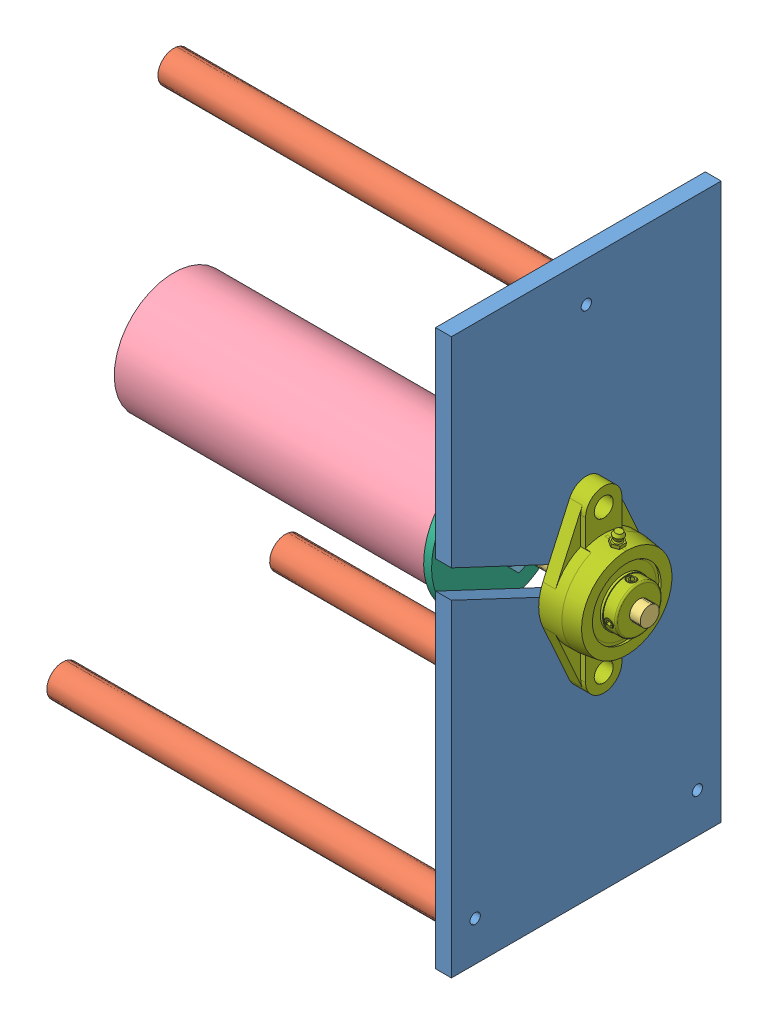
SolidWorks assembly TopRumpf, configuration Standard. Lengths in mm.
Overall size (300 350 170).
11 component instances, 7 part files, 21 mates.
Components (placement in the parent):
- Kopfteil_Rumpf-2: Kopfteil_Rumpf [Standard] at (250 0 0) x (0 0 -1) z (1 0 0) size (170 350 10)
- Kunststoffstab-1: Kunststoffstab [Standard] at (0 150 0) x (0 -0.985047 0.172283) z (1 0 0) size (20 20 250)
- Kunststoffstab-2: Kunststoffstab [Standard] at (0 -150 70) x (0 -0.332904 0.942961) z (1 0 0) size (20 20 250)
- Kunststoffstab-3: Kunststoffstab [Standard] at (0.4347 -150 -70) x (0 -0.626409 -0.779495) z (1 0 0) size (20 20 250)
- Rolle^TopRumpf-1: Rolle^TopRumpf [Standard] at (0 -201.8271 15.2917) x (1 0 0) z (0 0.91625 0.400607) size (300 85 85) (virtual)
  - Rundstahl 8mm-1: Rundstahl 8mm [Standard] at (300 94.8643 178.7981) x (0 0.566472 0.824081) z (-1 0 0) size (12 12 300)
  - Rolle-1: Rolle [Standard] at (0 94.8643 178.7981) x (0 0 -1) z (1 0 0) size (75 75 200)
  - shf12-1: shf12 [Standard] at (205 94.8643 178.7981) size (13.01 28 47)
  - Rollenaufnahme-1: Rollenaufnahme [Standard] at (200 94.8643 178.7981) x (0 0 1) z (-1 0 0) size (85 85 15)
- Baugr2^TopRumpf-1: Baugr2^TopRumpf [Standard] at (185.0438 -39.7683 25.0936) (suppressed, hidden, virtual)
- 24215-12201-1: 24215-12201 [Standard] at (260 0 0) x (0 1 0) z (0 0 -1) size (113 33.3 60)
Mates (geometry in assembly coordinates):
- Deckungsgleich17: coincident: point of Kunststoffstab-2; plane of assembly
- Konzentrisch24: concentric aligned: circle of Kunststoffstab-3; cylinder of Kopfteil_Rumpf-2 through (260 -150 -70) axis (1 0 0) radius 3.25
- Konzentrisch25: concentric aligned: circle of Kunststoffstab-1; circle of Kopfteil_Rumpf-2
- Konzentrisch26: concentric aligned: circle of Kunststoffstab-2; cylinder of Kopfteil_Rumpf-2 through (260 -150 70) axis (1 0 0) radius 3.25
- Deckungsgleich27: coincident anti-aligned: plane of Kunststoffstab-1 through (0 150 0) normal (-1 0 0)
- Parallel7: parallel aligned: plane of Kopfteil_Rumpf-2 through (260 175 -85) normal (0 1 0)
- Deckungsgleich33: coincident anti-aligned: plane of Kopfteil_Rumpf-2 through (250 0 0) normal (-1 0 0); plane of Kunststoffstab-1 through (250 150 0) normal (1 0 0)
- Abstand1: distance = 500 mm aligned: plane of Kunststoffstab-1 through (0 150 0) normal (-1 0 0); plane of Baugr2^TopRumpf-1/Innenring-1 through (500 0 0) normal (-1 0 0)
- Parallel8: parallel aligned: plane of Baugr2^TopRumpf-1 through (185.0438 -39.7683 25.0936) normal (0 0 1)
- Deckungsgleich36: coincident anti-aligned: plane of Baugr1^TopRumpf-1/Rundstahl 8mm-1 through (0 0 0) normal (-1 0 0)
- Deckungsgleich37: coincident: plane of Baugr1^TopRumpf-1/Rundstahl 8mm-1 through (0 0 0) normal (-1 0 0)
- Deckungsgleich38: coincident: unknown of Baugr1^TopRumpf-1/Rundstahl 8mm-1
- Konzentrisch34: concentric aligned: cylinder of Rolle^TopRumpf-1/Rundstahl 8mm-1 through (0 0 0) axis (-1 0 0) radius 6; line of Baugr2^TopRumpf-1/Halbkugel-1 through (540 0 0) axis (-1 0 0)
- Konzentrisch35: concentric aligned: cylinder of Kopfteil_Rumpf-2 through (260 45 0) axis (1 0 0) radius 3.25; cylinder of Baugr1^TopRumpf-1/HousingMitKugellager-1/HousingKugellagerDeckel-2 through (331 25 0) axis (1 0 0) radius 2.75
- Konzentrisch36: concentric aligned: cylinder of Kopfteil_Rumpf-2 through (260 45 0) axis (1 0 0) radius 3.25; cylinder of Baugr1^TopRumpf-1/HousingMitKugellager-1/HousingKugellagerDeckel-2 through (331 25 0) axis (1 0 0) radius 2.75
- Konzentrisch37: concentric aligned: cylinder of Kopfteil_Rumpf-2 through (260 -45 0) axis (1 0 0) radius 3.25; cylinder of Baugr1^TopRumpf-1/HousingMitKugellager-1/HousingKugellagerDeckel-2 through (331 -25 0) axis (1 0 0) radius 2.75
- Deckungsgleich39: coincident anti-aligned: plane of Kopfteil_Rumpf-2 through (260 0 0) normal (1 0 0); plane of Baugr1^TopRumpf-1/HousingMitKugellager-1/HousingKugellagerDeckel-1 through (310 0 16.6831) normal (-1 0 0)
- Konzentrisch38: concentric aligned: cylinder of Baugr1^TopRumpf-1/Rundstahl 8mm-1 through (0 0 0) axis (1 0 0) radius 6; cylinder of 24215-12201-1 through (262.3 0 0) axis (1 0 0) radius 6
- Konzentrisch39: concentric aligned: cylinder of Kopfteil_Rumpf-2 through (260 45 0) axis (1 0 0) radius 3.25; cylinder of 24215-12201-1 through (271 45 0) axis (1 0 0) radius 6
- Konzentrisch40: concentric aligned: cylinder of Kopfteil_Rumpf-2 through (260 -45 0) axis (1 0 0) radius 3.25; cylinder of 24215-12201-1 through (271 -45 0) axis (1 0 0) radius 6
- Deckungsgleich40: coincident anti-aligned: plane of Kopfteil_Rumpf-2 through (260 0 0) normal (1 0 0); plane of 24215-12201-1 through (260 21.5 0) normal (-1 0 0)
